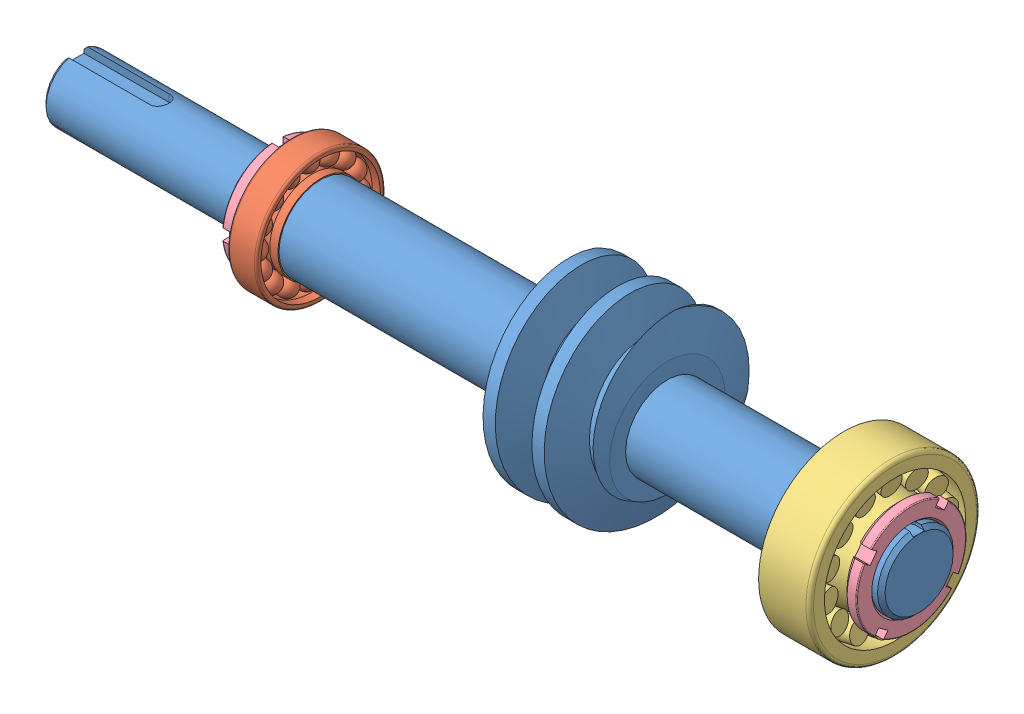
SolidWorks assembly sklop vratila 1, configuration Default. Lengths in mm.
Overall size (446 103.64 103.64).
5 component instances, 4 part files, 8 mates.
Components (placement in the parent):
- vratilo 1-1: vratilo 1 [Default] at origin size (446 97.97 96)
- lezaj 6008-1: lezaj 6008 [Default] at (-100.5 0 0) size (15 68 68)
- lezaj 32308-1: lezaj 32308 [Default] at (194.5 0 0) x (-1 0 0) z (0 -0.986237 -0.165341) size (33 90 90)
- pritezna navrtka lezaja KM8-1: pritezna navrtka lezaja KM8 [Default] at (211 0 0) x (0 0.803271 -0.595614) z (0 -0.595614 -0.803271) size (57.75 8.03 57.75)
- pritezna navrtka lezaja KM8-2: pritezna navrtka lezaja KM8 [Default] at (-108 0 0) x (0 1 0) z (0 0 1) size (57.75 8.03 57.75)
Mates (geometry in assembly coordinates):
- Concentric1: concentric aligned: cylinder of vratilo 1-1 through (-223 0 0) axis (-1 0 0) radius 17; cylinder of lezaj 6008-1 through (-124.2338 0 0) axis (-1 0 0) radius 20
- Coincident1: coincident anti-aligned: plane of vratilo 1-1 through (-93 20 0) normal (-1 0 0); plane of lezaj 6008-1 through (-93 20 0) normal (1 0 0)
- Concentric2: concentric anti-aligned: cylinder of vratilo 1-1 through (-223 0 0) axis (-1 0 0) radius 20; cylinder of lezaj 32308-1 through (211 0 0) axis (1 0 0) radius 20
- Coincident2: coincident anti-aligned: plane of vratilo 1-1 through (178 20 0) normal (1 0 0); plane of lezaj 32308-1 through (178 4.9602 -29.5871) normal (-1 0 0)
- Concentric3: concentric anti-aligned: cylinder of vratilo 1-1 through (-223 0 0) axis (-1 0 0) radius 22; cylinder of pritezna navrtka lezaja KM8-1 through (211 0 0) axis (1 0 0) radius 20
- Coincident3: coincident anti-aligned: plane of lezaj 32308-1 through (211 3.3068 -19.7247) normal (1 0 0); plane of pritezna navrtka lezaja KM8-1 through (211 0 0) normal (-1 0 0)
- Concentric4: concentric aligned: cylinder of vratilo 1-1 through (-223 0 0) axis (-1 0 0) radius 17; cylinder of pritezna navrtka lezaja KM8-2 through (-108 0 0) axis (-1 0 0) radius 20
- Coincident4: coincident anti-aligned: plane of lezaj 6008-1 through (-108 20 0) normal (-1 0 0); plane of pritezna navrtka lezaja KM8-2 through (-108 0 0) normal (1 0 0)
